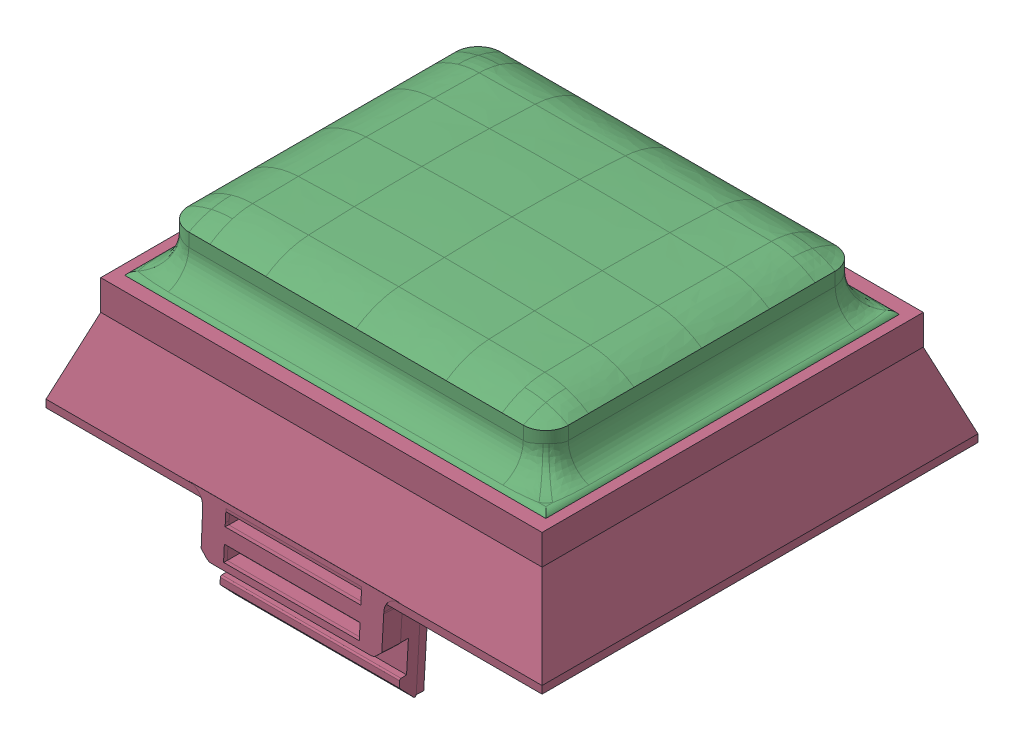
SolidWorks assembly BoardNew, configuration 默认. Lengths in mm.
Overall size (33 18.3 29.5).
5 component instances, 5 part files, 13 mates.
Components (placement in the parent):
- Boardlensall-1: Boardlensall [默认] at origin size (28.33 2.18 23.83)
- BoardInsideSkin-1: BoardInsideSkin [默认] at (0.0001 0 0.2499) size (23.8 5.48 19.29)
- BoardTopskin-1: BoardTopskin [默认] at (0.0001 2 0.2499) size (28.02 6.25 23.52)
- BoardSupportBase-2: BoardSupportBase [默认] at origin size (33 14.05 29.5)
- chessboard-1: chessboard [默认] at (-4.7946 23.7 -14.5409) x (1 0 0) z (0 -1 0) size (22.5 16.35 0.4)
Mates (geometry in assembly coordinates):
- 同心2: concentric anti-aligned: cylinder of BoardInsideSkin-1 through (10.8751 17.7531 8.6249) axis (0 1 0) radius 0.7; cylinder of Board3Con1612611OriginalSkin_TOP-1 through (10.8751 24 8.6249) axis (0 -1 0) radius 0.7
- 同心3: concentric anti-aligned: cylinder of BoardInsideSkin-1 through (10.8751 17.7531 -9.1251) axis (0 1 0) radius 0.7; cylinder of Board3Con1612611OriginalSkin_TOP-1 through (10.8751 24 -9.1251) axis (0 -1 0) radius 0.7
- 重合4: coincident aligned: plane of BoardInsideSkin-1 through (10.8751 19 -9.1251) normal (0 -1 0); plane of Board3Con1612611OriginalSkin_TOP-1 through (0.0001 19 0.2499) normal (0 -1 0)
- 重合6: coordinate: point of BoardSupportBase-2
- 重合7: coincident anti-aligned: plane of lensall-1 through (13.75 19 -11.5) normal (0.939693 0.34202 0); plane of BoardSupportBase-2 through (13.75 19 12.7803) normal (-0.939693 -0.34202 0)
- 同心5: concentric aligned: cylinder of lensall-1 through (13.3294 18.6938 -11.0794) axis (-0.323616 0.889126 0.323616) radius 0.5; cylinder of BoardSupportBase-2 through (10.7866 25.6801 -8.5366) axis (-0.323616 0.889126 0.323616) radius 0.5
- 重合8: coincident anti-aligned: plane of lensall-1 through (0 18 0) normal (0 -1 0); plane of BoardSupportBase-2 through (0 18 0) normal (0 1 0)
- 重合9: coincident anti-aligned: plane of lensall-1 through (0 19 0) normal (0 1 0); plane of Board3Con1612611OriginalSkin_TOP-1 through (0.0001 19 0.2499) normal (0 -1 0)
- 重合10: coincident anti-aligned: plane of Board3Con1612611OriginalSkin_TOP-1 through (0.0001 19 11.7499) normal (0 0 1); plane of BoardSupportBase-2 through (-13.5999 21 11.7499) normal (0 0 -1)
- 重合11: coincident anti-aligned: plane of Board3Con1612611OriginalSkin_TOP-1 through (14.0001 19 0.2499) normal (1 0 0); plane of BoardSupportBase-2 through (14.0001 21 11.7499) normal (-1 0 0)
- 宽度1: width aligned: plane of BoardInsideSkin-1 through (11.5751 17.7531 -9.1251) normal (1 0 0); plane of BoardInsideSkin-1 through (-12.0749 17.7531 -9.1251) normal (-1 0 0); plane of chessboard-1 through (11.0001 23.3 1.7749) normal (1 0 0); plane of chessboard-1 through (-11.4999 23.3 -2.3251) normal (-1 0 0)
- 宽度2: width aligned: plane of BoardInsideSkin-1 through (-11.3749 17.7531 -9.8251) normal (0 0 -1); plane of BoardInsideSkin-1 through (-11.3749 17.7531 9.3249) normal (0 0 1); plane of chessboard-1 through (-3.2999 23.3 -8.4251) normal (0 0 -1); plane of chessboard-1 through (-5.3499 23.3 7.9249) normal (0 0 1)
- 重合12: coincident aligned: line of BoardInsideSkin-1 through (-11.4999 23.7 5.8749) axis (0 0 -1); line of chessboard-1 through (-11.4999 23.7 5.8749) axis (0 0 -1)
